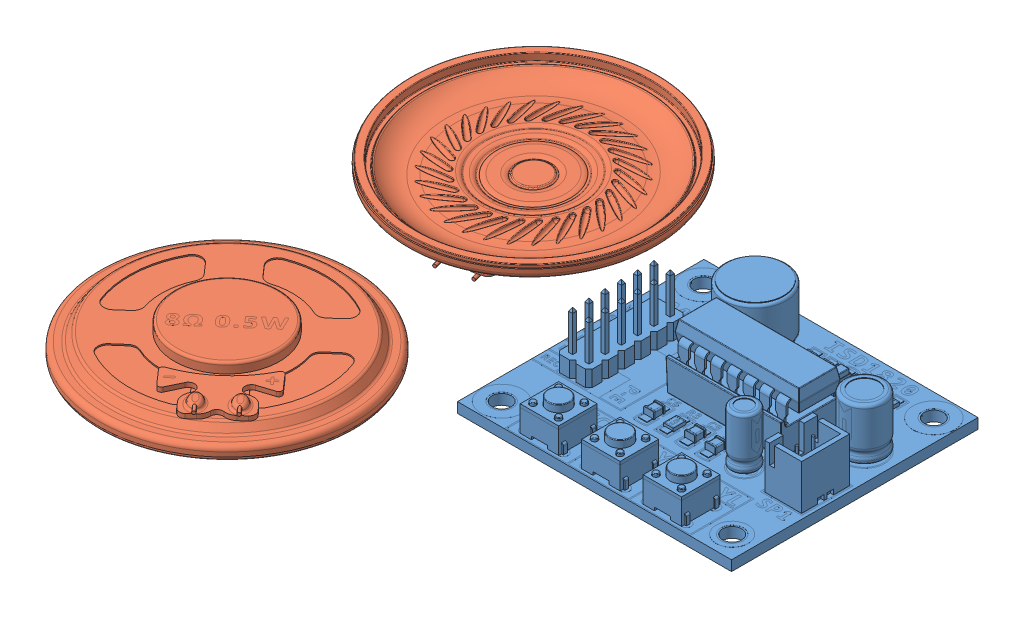
SolidWorks assembly Assem1, configuration Default. Lengths in mm.
Overall size (97.88 11.64 97.52).
3 component instances, 2 part files, 1 mates.
Components (placement in the parent):
- ISD1820 Voice Recorder-1: ISD1820 Voice Recorder [Default] at origin size (42.8 11.64 38.5)
- Speaker 8 Ohm 0.5W-1: Speaker 8 Ohm 0.5W [Default] at (-48.26 2.26 28.3805) x (0.752699 0 -0.658365) z (-0.658365 0 -0.752699) size (40 5 40)
- Speaker 8 Ohm 0.5W-2: Speaker 8 Ohm 0.5W [Default] at (-45.202 -1.2943 -16.4883) x (-0.966791 0.006128 0.255496) z (-0.255023 0.04223 -0.966012) size (40 5 40)
Mates (geometry in assembly coordinates):
- Coincident1: coincident aligned: plane of ISD1820 Voice Recorder-1 through (0 -2.74 0) normal (0 -1 0); plane of Speaker 8 Ohm 0.5W-1 through (-33.3565 -2.74 15.3449) normal (0 -1 0)
